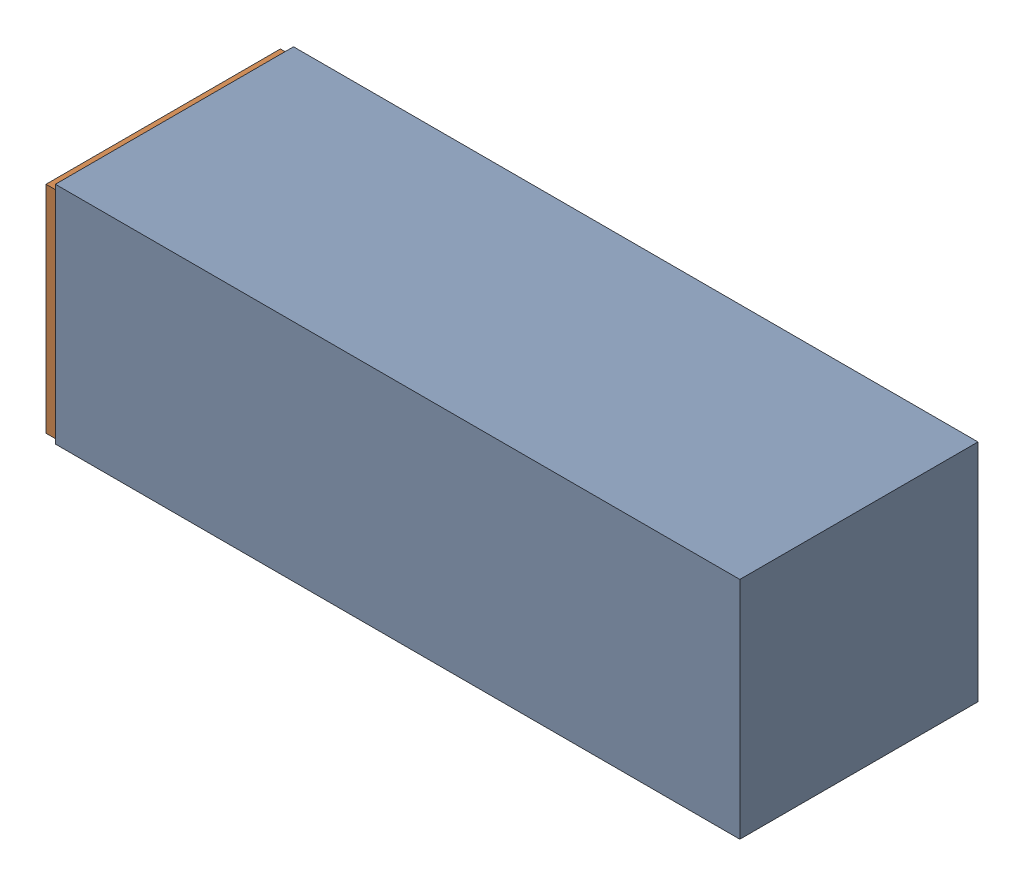
SolidWorks assembly H1, configuration Default. Lengths in mm.
Overall size (46.99 15.24 16.13).
4 component instances, 2 part files, 0 mates.
Components (placement in the parent):
- 407985440-1: 407985440 [Default] at (47.1043 64.643 -16.5329) size (46.35 15.24 16.13)
  - Extruded_4-1: Extruded_4 [Default] at origin size (46.35 15.24 16.13)
- 407985312-1: 407985312 [Default] at (23.6093 64.643 -16.2789) size (0.64 14.61 15.88)
  - Extruded_5-1: Extruded_5 [Default] at origin size (0.64 14.61 15.88)
